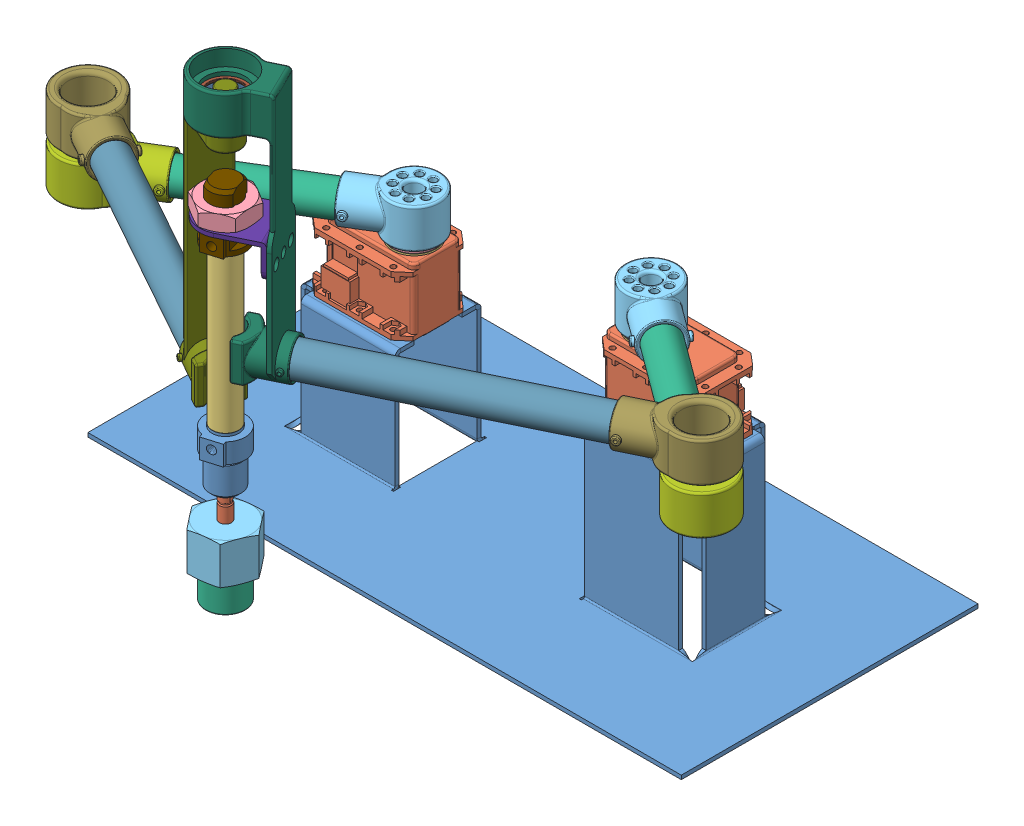
SolidWorks assembly Assem2, configuration Default. Lengths in mm.
Overall size (391.21 270.94 245.24).
67 component instances, 24 part files, 81 mates.
Components (placement in the parent):
- Frame-1: Frame [Default] at origin size (300 81.85 150)
- Motor-1: Motor [Default] at (-60 74.85 0) x (0 0 1) z (0 1 0) size (35.6 50.6 41.85)
- Motor-3: Motor [Default] at (60 94.85 0.2) x (0 0 -1) z (0 1 0) size (35.6 50.6 41.85)
- THRUST_WASHER-1: THRUST_WASHER [Default] at (-60 92.6 0) size (22 5.73 22)
- THRUST_WASHER-2: THRUST_WASHER [Default] at (60 112.6 0.2) size (22 5.73 22)
- HN07-N101 (1)-1: HN07-N101 (1) [Default] at (-60 93.45 0) x (0.853669 0 -0.520816) z (0.520816 0 0.853669) size (22 5.86 22)
- HN07-N101 (1)-2: HN07-N101 (1) [Default] at (60 113.45 0.2) x (0.804977 0 0.593306) z (-0.593306 0 0.804977) size (22 5.86 22)
- Coupler-1: Coupler [Default] at (74.4514 115.45 22.0283) x (0.804977 0 0.593306) z (-0.593306 0 0.804977) size (40 20.56 26)
- Coupler-3: Coupler [Default] at (-85.6724 95.45 5.1231) x (-0.853669 0 0.520816) z (-0.520816 0 -0.853669) size (40 20.56 26)
- Link 1-4-2: Link 1-4 [Default] at (-147.3125 105.45 53.2686) x (-0.520816 0 -0.853669) z (0 -1 0) size (16 88.7 16)
- Link 1-4-3: Link 1-4 [Default] at (142.3324 125.45 60.8828) x (-0.593306 0 0.804977) z (0 -1 0) size (16 88.7 16)
- Lower Joint-1: Lower Joint [Default] at (-188.4277 115.45 83.0539) x (-0.853669 0 0.520816) z (0.520816 0 0.853669) size (64.61 20.56 30)
- Lower Joint-2: Lower Joint [Default] at (185.4545 135.45 87.6802) x (0.804977 0 0.593306) z (0.593306 0 -0.804977) size (64.61 20.56 30)
- SKF_W_619_9_2Z-1: SKF_W_619_9_2Z [Default] at (156.5973 126.45 71.3967) x (0 1 0) z (0.998922 0 -0.046418) size (6 20 20)
  - SKF_W_619_9_2Z_12-1: SKF_W_619_9_2Z_12 [Default] x (1 0 0) z (0 -0.707107 0.707107) size (3.18 3.18 3.17)
  - SKF_W_619_9_2Z_12-2: SKF_W_619_9_2Z_12 [Default] x (1 0 0) z (0 -1 0) size (3.18 3.18 3.17)
  - SKF_W_619_9_2Z_12-3: SKF_W_619_9_2Z_12 [Default] x (1 0 0) z (0 -0.707107 -0.707107) size (3.18 3.18 3.17)
  - SKF_W_619_9_2Z_12-4: SKF_W_619_9_2Z_12 [Default] x (1 0 0) z (0 0 -1) size (3.18 3.18 3.17)
  - SKF_W_619_9_2Z_12-5: SKF_W_619_9_2Z_12 [Default] x (1 0 0) z (0 0.707107 -0.707107) size (3.18 3.18 3.17)
  - SKF_W_619_9_2Z_12-6: SKF_W_619_9_2Z_12 [Default] x (1 0 0) z (0 1 0) size (3.18 3.18 3.17)
  - SKF_W_619_9_2Z_12-7: SKF_W_619_9_2Z_12 [Default] x (1 0 0) z (0 0.707107 0.707107) size (3.18 3.18 3.17)
  - SKF_W_619_9_2Z_12-8: SKF_W_619_9_2Z_12 [Default] at origin size (3.18 3.18 3.17)
  - SKF_W_619_9_2Z_21-1: SKF_W_619_9_2Z_21 [Default] at origin size (6 20 20)
  - SKF_W_619_9_2Z_23-1: SKF_W_619_9_2Z_23 [Default] at origin size (6 17.44 17.44)
- SKF_W_619_9_2Z-2: SKF_W_619_9_2Z [Default] at (-162.4403 106.45 62.4979) x (0 1 0) z (0.998922 0 -0.046418) size (6 20 20)
  - SKF_W_619_9_2Z_12-1: SKF_W_619_9_2Z_12 [Default] x (1 0 0) z (0 -0.707107 0.707107) size (3.18 3.18 3.17)
  - SKF_W_619_9_2Z_12-2: SKF_W_619_9_2Z_12 [Default] x (1 0 0) z (0 -1 0) size (3.18 3.18 3.17)
  - SKF_W_619_9_2Z_12-3: SKF_W_619_9_2Z_12 [Default] x (1 0 0) z (0 -0.707107 -0.707107) size (3.18 3.18 3.17)
  - SKF_W_619_9_2Z_12-4: SKF_W_619_9_2Z_12 [Default] x (1 0 0) z (0 0 -1) size (3.18 3.18 3.17)
  - SKF_W_619_9_2Z_12-5: SKF_W_619_9_2Z_12 [Default] x (1 0 0) z (0 0.707107 -0.707107) size (3.18 3.18 3.17)
  - SKF_W_619_9_2Z_12-6: SKF_W_619_9_2Z_12 [Default] x (1 0 0) z (0 1 0) size (3.18 3.18 3.17)
  - SKF_W_619_9_2Z_12-7: SKF_W_619_9_2Z_12 [Default] x (1 0 0) z (0 0.707107 0.707107) size (3.18 3.18 3.17)
  - SKF_W_619_9_2Z_12-8: SKF_W_619_9_2Z_12 [Default] at origin size (3.18 3.18 3.17)
  - SKF_W_619_9_2Z_21-1: SKF_W_619_9_2Z_21 [Default] at origin size (6 20 20)
  - SKF_W_619_9_2Z_23-1: SKF_W_619_9_2Z_23 [Default] at origin size (6 17.44 17.44)
- DNH-20 (Retaining Ring - Housing for Part 2)-1: DNH-20 (Retaining Ring - Housing for Part 2) [Default] at (-162.4403 105.955 62.4979) size (21 1.05 21.02)
- DNH-20 (Retaining Ring - Housing for Part 2)-2: DNH-20 (Retaining Ring - Housing for Part 2) [Default] at (156.5973 125.955 71.3967) size (21 1.05 21.02)
- Upper Joint-2: Upper Joint [Default] at (187.9263 138.45 60.6085) x (0.899114 0 -0.437715) z (0.437715 0 0.899114) size (64.61 35.28 30)
- Upper Joint-3: Upper Joint [Default] at (-189.2091 118.45 42.9703) x (-0.873317 0 -0.487153) z (0.487153 0 -0.873317) size (64.61 35.28 30)
- ES-9 (Retaining Ring - Shaft Part 2)-1: ES-9 (Retaining Ring - Shaft Part 2) [Default] at (-162.4403 106.13 62.4979) size (10 0.85 10.1)
- ES-9 (Retaining Ring - Shaft Part 2)-2: ES-9 (Retaining Ring - Shaft Part 2) [Default] at (156.5973 126.13 71.3967) size (10 0.85 10.1)
- Link 2-3-1: Link 2-3 [Default] at (-146.9644 128.45 71.1307) x (0 1 0) z (0.487153 0 -0.873317) size (16 148.13 16)
- Link 2-3-2: Link 2-3 [Default] at (140.6642 148.45 79.1534) x (0 -1 0) z (-0.437715 0 -0.899114) size (16 148.13 16)
- Upper End Joint-1: Upper End Joint [Default] at (-5.2432 157.95 150.1854) x (-0.899114 0 0.437715) z (0.437715 0 0.899114) size (42.15 130.25 30)
- Lower End Joint-2: Lower End Joint [Default] at (-5.2432 118.95 150.1854) x (0.873317 0 0.487153) z (-0.487153 0 0.873317) size (34.65 143.26 22.04)
- SKF_W_619_9_2Z-3: SKF_W_619_9_2Z [Default] at (-5.2432 251.9422 150.1854) x (0 1 0) z (0 0 1) size (6 20 20)
  - SKF_W_619_9_2Z_12-1: SKF_W_619_9_2Z_12 [Default] x (1 0 0) z (0 -0.707107 0.707107) size (3.18 3.18 3.17)
  - SKF_W_619_9_2Z_12-2: SKF_W_619_9_2Z_12 [Default] x (1 0 0) z (0 -1 0) size (3.18 3.18 3.17)
  - SKF_W_619_9_2Z_12-3: SKF_W_619_9_2Z_12 [Default] x (1 0 0) z (0 -0.707107 -0.707107) size (3.18 3.18 3.17)
  - SKF_W_619_9_2Z_12-4: SKF_W_619_9_2Z_12 [Default] x (1 0 0) z (0 0 -1) size (3.18 3.18 3.17)
  - SKF_W_619_9_2Z_12-5: SKF_W_619_9_2Z_12 [Default] x (1 0 0) z (0 0.707107 -0.707107) size (3.18 3.18 3.17)
  - SKF_W_619_9_2Z_12-6: SKF_W_619_9_2Z_12 [Default] x (1 0 0) z (0 1 0) size (3.18 3.18 3.17)
  - SKF_W_619_9_2Z_12-7: SKF_W_619_9_2Z_12 [Default] x (1 0 0) z (0 0.707107 0.707107) size (3.18 3.18 3.17)
  - SKF_W_619_9_2Z_12-8: SKF_W_619_9_2Z_12 [Default] at origin size (3.18 3.18 3.17)
  - SKF_W_619_9_2Z_21-1: SKF_W_619_9_2Z_21 [Default] at origin size (6 20 20)
  - SKF_W_619_9_2Z_23-1: SKF_W_619_9_2Z_23 [Default] at origin size (6 17.44 17.44)
- DNH-20 (Retaining Ring - Housing for Part 2)-3: DNH-20 (Retaining Ring - Housing for Part 2) [Default] at (-5.2432 258.4372 150.1854) size (21 1.05 21.02)
- ES-9 (Retaining Ring - Shaft Part 2)-3: ES-9 (Retaining Ring - Shaft Part 2) [Default] at (-5.2432 259.27 150.1854) size (10 0.85 10.1)
- Foot Bracket-1: Foot Bracket [070021] at (12.739 205.95 141.4311) x (-0.437715 0 -0.899114) z (0 1 0) size (26 33 18)
- Janatics-A51, A52 Series-1: Janatics-A51, A52 Series [A51, A52 Series] at (-5.2432 220.95 150.1854) x (0 1 0) z (0.288014 0 0.957626) size (156 20 20.5)
  - Janatics-A51, A52 Series_REC-1(new)-1: Janatics-A51, A52 Series_REC-1(new) [DIA 12] x (-1 0 0) z (0 1 0) size (33 20.5 20)
  - Janatics-A51, A52 Series_FEC(new)-1: Janatics-A51, A52 Series_FEC(new) [Default] at (-135 0 0) x (1 0 0) z (0 -1 0) size (33 20.5 20)
  - Janatics-A51, A52 Series_piston rod (10C)(new)-1: Janatics-A51, A52 Series_piston rod (10C)(new) [DIA 12] at (-33 0 0) x (-1 0 0) z (0 -0.99731 -0.073305) size (123 12 12)
  - Janatics-A51, A52 Series_cylinder barral (10A)(new)-1: Janatics-A51, A52 Series_cylinder barral (10A)(new) [Dia 12] at (564.2482 -0.0004 -0.0002) x (1 0 0) z (0 0.366126 -0.930565) size (78.3 13.3 13.3)
- Janatics-A51, A52 Series_lock nut Dia12-1: Janatics-A51, A52 Series_lock nut Dia12 [Dia 12] at (-5.2432 205.95 150.1854) x (0 1 0) z (0.00654 0 0.999979) size (8 24 27.71)
- Nut and Bolt-2: Nut and Bolt [Default] at (-5.2432 71.95 150.1854) x (0.99058 0 -0.136936) z (-0.136936 0 -0.99058) size (30 27.12 25.98)
- Electromagnet-1: Electromagnet [Default] at (-5.2432 51.95 150.1854) x (1 0 0) z (0 0 -1) size (20 15.03 20)
Mates (geometry in assembly coordinates):
- Coincident1: coincident anti-aligned: plane of Frame-1 through (0 59.85 0) normal (0 1 0); plane of Motor-1 through (-60 59.85 0) normal (0 -1 0)
- Concentric1: concentric anti-aligned: cylinder of Frame-1 through (-72.5 -2 15) axis (0 1 0) radius 1.35; cylinder of Motor-1 through (-72.5 74.85 15) axis (0 -1 0) radius 1.35
- Concentric2: concentric anti-aligned: cylinder of Frame-1 through (-55.5 -2 15) axis (0 1 0) radius 1.35; cylinder of Motor-1 through (-55.5 74.85 15) axis (0 -1 0) radius 1.35
- Coincident2: coincident anti-aligned: plane of Frame-1 through (0 79.85 0) normal (0 1 0); plane of Motor-3 through (60 79.85 0.2) normal (0 -1 0)
- Concentric3: concentric anti-aligned: cylinder of Frame-1 through (95.8 -2 -8.3) axis (0 1 0) radius 1.35; cylinder of Motor-3 through (95.8 94.85 -8.3) axis (0 -1 0) radius 1.35
- Concentric4: concentric anti-aligned: cylinder of Frame-1 through (95.8 -2 8.7) axis (0 1 0) radius 1.35; cylinder of Motor-3 through (95.8 94.85 8.7) axis (0 -1 0) radius 1.35
- Concentric5: concentric anti-aligned: circle of Motor-1; circle of THRUST_WASHER-1
- Coincident3: coincident anti-aligned: plane of Motor-1 through (-60 92.6 0) normal (0 1 0); plane of THRUST_WASHER-1 through (-60 92.6 0) normal (0 -1 0)
- Coincident5: coincident anti-aligned: plane of Motor-3 through (60 112.6 0.2) normal (0 1 0); plane of THRUST_WASHER-2 through (60 112.6 0.2) normal (0 -1 0)
- Concentric6: concentric anti-aligned: circle of Motor-3; circle of THRUST_WASHER-2
- Concentric7: concentric aligned: circle of THRUST_WASHER-1; circle of HN07-N101 (1)-1
- Coincident7: coincident anti-aligned: plane of THRUST_WASHER-1 through (-60 93.45 0) normal (0 1 0); plane of HN07-N101 (1)-1 through (-60 93.45 0) normal (0 -1 0)
- Coincident8: coincident anti-aligned: plane of THRUST_WASHER-2 through (60 113.45 0.2) normal (0 1 0); plane of HN07-N101 (1)-2 through (60 113.45 0.2) normal (0 -1 0)
- Concentric8: concentric aligned: circle of THRUST_WASHER-2; circle of HN07-N101 (1)-2
- Coincident12: coincident anti-aligned: plane of HN07-N101 (1)-2 through (60 115.45 0.2) normal (0 1 0); plane of Coupler-1 through (60 115.45 0.2) normal (0 -1 0)
- Concentric9: concentric anti-aligned: circle of HN07-N101 (1)-2; circle of Coupler-1
- Coincident13: coincident anti-aligned: plane of HN07-N101 (1)-1 through (-60 95.45 0) normal (0 1 0); plane of Coupler-3 through (-60 95.45 0) normal (0 -1 0)
- Concentric10: concentric anti-aligned: circle of HN07-N101 (1)-1; circle of Coupler-3
- Coincident14: coincident anti-aligned: circle of Link 1-4-1; plane of Link 1-4-2 through (-147.3125 105.45 53.2686) normal (-0.853669 0 0.520816)
- Concentric11: concentric anti-aligned: cylinder of HN07-N101 (1)-1 through (-52.6698 91.6857 3.2045) axis (0 1 0) radius 0.8; cylinder of Coupler-3 through (-52.6698 115.7295 3.2045) axis (0 -1 0) radius 1.2
- Concentric13: concentric anti-aligned: cylinder of HN07-N101 (1)-2 through (66.4398 111.6857 4.9464) axis (0 1 0) radius 0.8; cylinder of Coupler-1 through (66.4398 135.7295 4.9464) axis (0 -1 0) radius 1.2
- Coincident21: coincident anti-aligned: plane of Coupler-1 through (70.9347 125.45 8.2594) normal (0.804977 0 0.593306); plane of Link 1-4-3 through (70.9347 125.45 8.2594) normal (-0.804977 0 -0.593306)
- Coincident22: coincident anti-aligned: plane of Coupler-1 through (70.9347 125.45 8.2594) normal (0.804977 0 0.593306); plane of Link 1-4-3 through (70.9347 125.45 8.2594) normal (-0.804977 0 -0.593306)
- Concentric14: concentric aligned: cylinder of Coupler-1 through (70.9347 125.45 8.2594) axis (0.804977 0 0.593306) radius 8; cylinder of Link 1-4-3 through (70.9347 125.45 8.2594) axis (0.804977 0 0.593306) radius 8
- Concentric15: concentric anti-aligned: cylinder of Coupler-1 through (86.1441 125.45 5.1798) axis (0.593306 0 -0.804977) radius 0.8; cylinder of Link 1-4-3 through (74.573 125.45 20.8792) axis (-0.593306 0 0.804977) radius 0.8
- Coincident23: coincident anti-aligned: plane of Coupler-3; plane of Link 1-4-2
- Concentric16: concentric aligned: cylinder of Coupler-3 through (-54.7924 105.45 -11.9125) axis (-0.400557 0 0.916272) radius 10; cylinder of Link 1-4-2 through (-65.4411 105.45 12.4465) axis (-0.400557 0 0.916272) radius 8
- Concentric17: concentric anti-aligned: cylinder of Coupler-3 through (-59.0737 105.45 26.5981) axis (0.916272 0 0.400557) radius 0.8; cylinder of Link 1-4-2 through (-76.9435 105.45 18.7861) axis (-0.916272 0 -0.400557) radius 0.8
- Coincident24: coincident anti-aligned: plane of Link 1-4-3 through (142.3324 125.45 60.8828) normal (0.804977 0 0.593306); plane of Lower Joint-2 through (142.3324 125.45 60.8828) normal (-0.804977 0 -0.593306)
- Concentric18: concentric anti-aligned: cylinder of Link 1-4-3 through (70.9347 125.45 8.2594) axis (0.804977 0 0.593306) radius 8; cylinder of Lower Joint-2 through (147.1622 125.45 64.4427) axis (-0.804977 0 -0.593306) radius 10
- Concentric19: concentric aligned: cylinder of Link 1-4-3 through (128.7312 125.45 60.7963) axis (-0.593306 0 0.804977) radius 0.8; cylinder of Lower Joint-2 through (126.6566 125.45 63.611) axis (-0.593306 0 0.804977) radius 0.8
- Coincident25: coincident anti-aligned: plane of Link 1-4-2; plane of Lower Joint-1
- Concentric20: concentric anti-aligned: cylinder of Link 1-4-2 through (-65.4411 105.45 12.4465) axis (-0.400557 0 0.916272) radius 8; cylinder of Lower Joint-1 through (-103.372 105.45 99.2131) axis (0.400557 0 -0.916272) radius 10
- Concentric23: concentric aligned: cylinder of Lower Joint-1 through (-107.0966 105.45 79.0314) axis (-0.916272 0 -0.400557) radius 0.8; cylinder of Link 1-4-2 through (-103.8927 105.45 80.4321) axis (-0.916272 0 -0.400557) radius 0.8
- Concentric24: concentric anti-aligned: cylinder of Lower Joint-2 through (156.5973 115.45 71.3967) axis (0 1 0) radius 15; cylinder of Upper Joint-1 through (180 146.3032 0.2) axis (0 -1 0) radius 15
- Concentric25: concentric aligned: cylinder of Lower Joint-2 through (156.5973 115.45 71.3967) axis (0 1 0) radius 15; cylinder of SKF_W_619_9_2Z-1/SKF_W_619_9_2Z_21-1 through (156.5973 176.45 71.3967) axis (0 1 0) radius 10
- Coincident27: coincident anti-aligned: plane of Lower Joint-2 through (156.5973 132.45 71.3967) normal (0 -1 0); plane of SKF_W_619_9_2Z-1/SKF_W_619_9_2Z_23-1 through (156.8201 132.45 76.1915) normal (0 1 0)
- Coincident29: coincident anti-aligned: plane of Lower Joint-1 through (-108.0668 112.45 109.9526) normal (0 -1 0); plane of SKF_W_619_9_2Z-2/SKF_W_619_9_2Z_23-1 through (-107.8441 112.45 114.7475) normal (0 1 0)
- Concentric26: concentric aligned: cylinder of Lower Joint-1 through (-108.0668 95.45 109.9526) axis (0 1 0) radius 15; cylinder of SKF_W_619_9_2Z-2/SKF_W_619_9_2Z_21-1 through (-108.0668 156.45 109.9526) axis (0 1 0) radius 10
- Coincident30: coincident anti-aligned: plane of Lower Joint-1 through (-108.0668 106.45 109.9526) normal (0 -1 0); plane of DNH-20 (Retaining Ring - Housing for Part 2)-1 through (-108.0668 106.45 99.6506) normal (0 1 0)
- Concentric27: concentric aligned: cylinder of Lower Joint-1 through (-108.0668 103.45 109.9526) axis (0 1 0) radius 10; circle of DNH-20 (Retaining Ring - Housing for Part 2)-1
- Coincident32: coincident anti-aligned: plane of Lower Joint-2 through (156.5973 126.45 71.3967) normal (0 -1 0); plane of DNH-20 (Retaining Ring - Housing for Part 2)-2 through (156.5973 126.45 61.0947) normal (0 1 0)
- Concentric28: concentric aligned: cylinder of Lower Joint-2 through (156.5973 115.45 71.3967) axis (0 1 0) radius 15; circle of DNH-20 (Retaining Ring - Housing for Part 2)-2
- Coincident33: coincident anti-aligned: plane of SKF_W_619_9_2Z-1/SKF_W_619_9_2Z_23-1 through (156.8201 132.45 76.1915) normal (0 1 0); plane of Upper Joint-2 through (156.5973 132.45 71.3967) normal (0 -1 0)
- Concentric29: concentric anti-aligned: cylinder of Lower Joint-2 through (156.5973 115.45 71.3967) axis (0 1 0) radius 15; cylinder of Upper Joint-2 through (156.5973 158.45 71.3967) axis (0 -1 0) radius 15
- Concentric30: concentric anti-aligned: cylinder of Lower Joint-1 through (-108.0668 95.45 109.9526) axis (0 1 0) radius 15; cylinder of Upper Joint-3 through (-108.0668 138.45 109.9526) axis (0 -1 0) radius 15
- Coincident34: coincident anti-aligned: plane of SKF_W_619_9_2Z-2/SKF_W_619_9_2Z_23-1 through (-107.8441 112.45 114.7475) normal (0 1 0); plane of Upper Joint-3 through (-108.0668 112.45 109.9526) normal (0 -1 0)
- Coincident35: coincident anti-aligned: plane of Upper Joint-3 through (-101.1137 106.45 114.5949) normal (0 -1 0); plane of ES-9 (Retaining Ring - Shaft Part 2)-1 through (-108.0668 106.45 105.0806) normal (0 1 0)
- Concentric31: concentric aligned: cylinder of Upper Joint-3 through (-108.0668 103.45 109.9526) axis (0 1 0) radius 4.5; circle of ES-9 (Retaining Ring - Shaft Part 2)-1
- Coincident37: coincident anti-aligned: plane of Upper Joint-2 through (151.2576 126.45 77.8298) normal (0 -1 0); plane of ES-9 (Retaining Ring - Shaft Part 2)-2 through (156.5973 126.45 66.5247) normal (0 1 0)
- Concentric32: concentric anti-aligned: circle of Lower Joint-2; circle of ES-9 (Retaining Ring - Shaft Part 2)-2
- Coincident52: coincident anti-aligned: plane of Upper Joint-2; plane of Link 2-3-2
- Concentric41: concentric anti-aligned: cylinder of Upper Joint-2 through (147.1051 148.45 100.8435) axis (0.769468 0 0.638685) radius 0.8; cylinder of Link 2-3-2 through (132.0979 148.45 88.387) axis (-0.769468 0 -0.638685) radius 0.8
- Concentric42: concentric anti-aligned: cylinder of Upper Joint-2 through (149.1113 148.45 80.4155) axis (-0.638685 0 0.769468) radius 10; cylinder of Link 2-3-2 through (50.6713 148.45 199.013) axis (0.638685 0 -0.769468) radius 8
- Concentric43: concentric aligned: cylinder of Link 2-3-2 through (50.6713 148.45 199.013) axis (0.638685 0 -0.769468) radius 8; cylinder of Upper End Joint-1 through (44.7619 148.45 206.1325) axis (0.638685 0 -0.769468) radius 8.0025
- Coincident53: coincident anti-aligned: plane of Link 2-3-2; plane of Upper End Joint-1
- Concentric44: concentric anti-aligned: cylinder of Link 2-3-2 through (50.8066 148.45 186.3243) axis (-0.769468 0 -0.638685) radius 0.8; cylinder of Upper End Joint-1 through (65.4265 148.45 198.4593) axis (0.769468 0 0.638685) radius 0.8
- Coincident56: coincident anti-aligned: plane of Upper Joint-3; plane of Link 2-3-1
- Concentric50: concentric aligned: cylinder of Upper Joint-3 through (-77.7931 128.45 116.3334) axis (0.555269 0 -0.831671) radius 0.8; cylinder of Link 2-3-1 through (-79.7384 128.45 119.247) axis (0.555269 0 -0.831671) radius 0.8
- Concentric51: concentric anti-aligned: cylinder of Upper Joint-3 through (-98.3189 128.45 116.4608) axis (0.831671 0 0.555269) radius 10; cylinder of Link 2-3-1 through (29.8658 128.45 202.0439) axis (-0.831671 0 -0.555269) radius 8
- Concentric52: concentric aligned: cylinder of Link 2-3-1 through (29.8658 128.45 202.0439) axis (-0.831671 0 -0.555269) radius 8; cylinder of Lower End Joint-2 through (37.5608 128.45 207.1816) axis (-0.831671 0 -0.555269) radius 9.5
- Coincident57: coincident anti-aligned: plane of Link 2-3-1; plane of Lower End Joint-2
- Concentric53: concentric aligned: cylinder of Link 2-3-1 through (26.116 128.45 189.9212) axis (0.555269 0 -0.831671) radius 0.8; circle of Lower End Joint-2
- Concentric54: concentric aligned: circle of Upper End Joint-1; circle of Lower End Joint-2
- Coincident58: coincident anti-aligned: plane of Upper End Joint-1 through (41.6339 251.9422 209.901) normal (0 1 0); plane of SKF_W_619_9_2Z-3/SKF_W_619_9_2Z_23-1 through (35.8289 251.9422 209.901) normal (0 -1 0)
- Concentric55: concentric aligned: cylinder of Upper End Joint-1 through (41.6339 248.9422 209.901) axis (0 1 0) radius 15; cylinder of SKF_W_619_9_2Z-3/SKF_W_619_9_2Z_21-1 through (41.6339 301.9422 209.901) axis (0 1 0) radius 10
- Coincident59: coincident anti-aligned: plane of Upper End Joint-1 through (41.6339 257.9422 209.901) normal (0 1 0); plane of DNH-20 (Retaining Ring - Housing for Part 2)-3 through (41.6339 257.9422 201.113) normal (0 -1 0)
- Concentric56: concentric aligned: circle of Lower End Joint-2; circle of DNH-20 (Retaining Ring - Housing for Part 2)-3
- Coincident60: coincident anti-aligned: plane of Lower End Joint-2 through (33.4628 258.95 204.4455) normal (0 1 0); plane of ES-9 (Retaining Ring - Shaft Part 2)-3 through (41.6339 258.95 205.533) normal (0 -1 0)
- Concentric57: concentric aligned: circle of Lower End Joint-2; circle of ES-9 (Retaining Ring - Shaft Part 2)-3
- Coincident62: coincident anti-aligned: plane of Upper End Joint-1; plane of Foot Bracket-1
- Concentric58: concentric anti-aligned: cylinder of Upper End Joint-1 through (43.2841 193.95 195.3872) axis (0.638685 0 -0.769468) radius 2.75; cylinder of Foot Bracket-1 through (53.2197 193.95 183.4171) axis (-0.638685 0 0.769468) radius 2.75
- Concentric59: concentric anti-aligned: cylinder of Upper End Joint-1 through (55.5956 193.95 205.6062) axis (0.638685 0 -0.769468) radius 2.75; cylinder of Foot Bracket-1 through (65.5312 193.95 193.6361) axis (-0.638685 0 0.769468) radius 2.75
- Concentric60: concentric anti-aligned: cylinder of Lower End Joint-2 through (41.6339 96.3226 209.901) axis (0 1 0) radius 8; cylinder of Janatics-A51, A52 Series-1/Janatics-A51, A52 Series_cylinder barral (10A)(new)-1 through (41.6339 118.95 209.901) axis (0 -1 0) radius 6.65
- Coincident63: coincident anti-aligned: plane of Foot Bracket-1 through (39.6144 203.95 191.9797) normal (0 -1 0); plane of Janatics-A51, A52 Series-1/Janatics-A51, A52 Series_REC-1(new)-1 through (43.7919 203.95 217.0839) normal (0 1 0)
- Concentric61: concentric anti-aligned: cylinder of Janatics-A51, A52 Series-1/Janatics-A51, A52 Series_REC-1(new)-1 through (41.6339 220.95 209.901) axis (0 1 0) radius 8; cylinder of Janatics-A51, A52 Series_lock nut Dia12-1 through (41.6339 205.95 209.901) axis (0 -1 0) radius 7.25
- Coincident64: coincident anti-aligned: plane of Foot Bracket-1 through (39.6144 205.95 191.9797) normal (0 1 0); plane of Janatics-A51, A52 Series_lock nut Dia12-1 through (41.5433 205.95 196.0449) normal (0 -1 0)
- Concentric62: concentric aligned: cylinder of Janatics-A51, A52 Series-1/Janatics-A51, A52 Series_FEC(new)-1 through (41.6339 85.95 209.901) axis (0 -1 0) radius 8; circle of Nut and Bolt-2
- Distance1: distance = 13 mm aligned: plane of Janatics-A51, A52 Series-1/Janatics-A51, A52 Series_piston rod (10C)(new)-1 through (-4.1709 64.95 152.9872) normal (0 -1 0); plane of Nut and Bolt-2 through (-5.2432 51.95 150.1854) normal (0 -1 0)
- Coincident66: coincident anti-aligned: plane of Nut and Bolt-2 through (41.6339 51.95 209.901) normal (0 -1 0); plane of Electromagnet-1 through (41.6339 51.95 209.901) normal (0 1 0)
- Concentric63: concentric anti-aligned: circle of Nut and Bolt-2; cylinder of Electromagnet-1 through (41.6339 36.95 209.901) axis (0 1 0) radius 10
